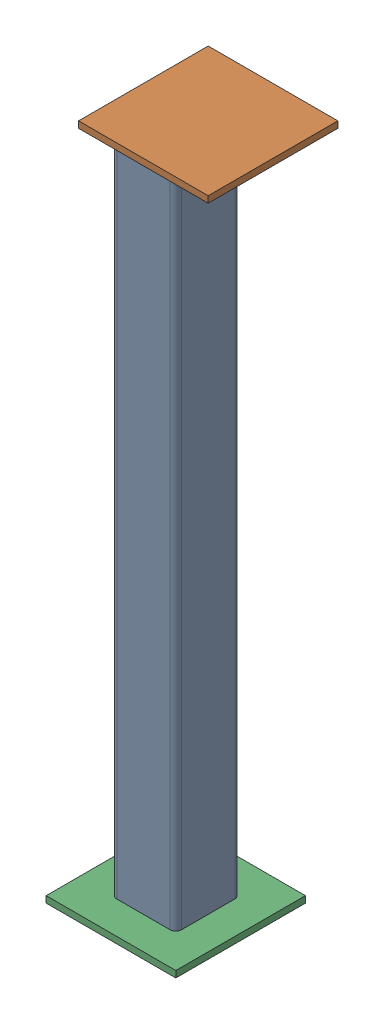
SolidWorks assembly castillo con placa, configuration Default. Lengths in mm.
Overall size (100 510 125).
3 component instances, 2 part files, 4 mates.
Components (placement in the parent):
- castillo-1: castillo [Default<As Machined>] at (56.6874 -444.1376 310.0195) size (50 500 50)
- placa banco de pruebas-1: placa banco de pruebas [Default] at (6.6874 55.8624 335.0195) size (100 5 100)
- placa banco de pruebas-2: placa banco de pruebas [Default] at (6.6874 -449.1376 260.0195) x (0 0 1) z (-1 0 0) size (100 5 100)
Mates (geometry in assembly coordinates):
- Distance5: distance = 25 mm aligned: plane of castillo-1 through (31.6874 55.8624 330.5195) normal (-1 0 0); plane of placa banco de pruebas-1 through (6.6874 60.8624 335.0195) normal (-1 0 0)
- Coincident5: coincident aligned: plane of castillo-1 through (36.1874 55.8624 335.0195) normal (0 0 1); plane of placa banco de pruebas-1 through (6.6874 60.8624 335.0195) normal (0 0 1)
- Coincident6: coincident anti-aligned: plane of castillo-1 through (36.1874 55.8624 289.5195) normal (0 1 0); plane of placa banco de pruebas-1 through (6.6874 55.8624 335.0195) normal (0 -1 0)
- ProfileCenter1: profile center: plane of placa banco de pruebas-2 through (6.6874 -444.1376 260.0195) normal (0 1 0); plane of castillo-1 through (36.1874 -444.1376 289.5195) normal (0 -1 0)
